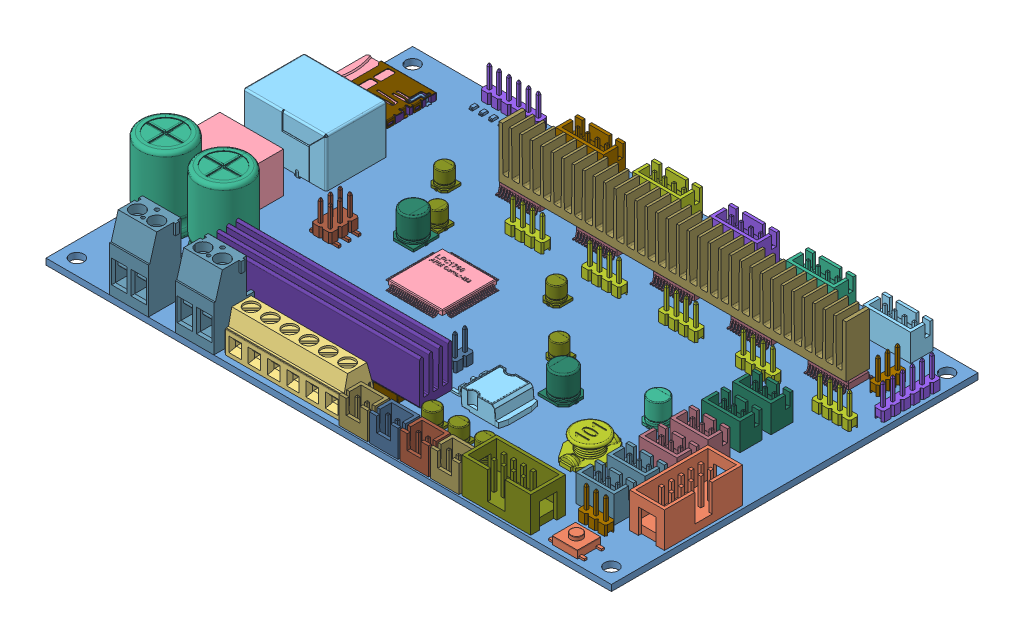
SolidWorks assembly MKS SBase V1.3, configuration Default. Lengths in mm.
Overall size (148.75 24.1 95).
84 component instances, 43 part files, 181 mates.
Components (placement in the parent):
- MKS SBase PCB-1: MKS SBase PCB [Default] at origin size (146.5 1.6 95)
- 10 pin male socket -2: 10 pin male socket  [Default] at (92.5901 0 -6.7406) x (0 0 -1) z (1 0 0) size (20.25 12.5 9) (hidden)
- 10 pin male socket -3: 10 pin male socket  [Default] at (92.5901 0 -28.4906) x (0 0 -1) z (1 0 0) size (20.25 12.5 9) (hidden)
- 6 pin terminal block-1: 6 pin terminal block [Default] at (-13.25 0 37.7021) size (30.6 13.8 8.3)
- USB socket-1: USB socket [Default] at (-15.2875 4.6912 16.0684) size (16.5 14.22 14.86)
- JST XH 4 Purple-1: JST XH 4 Purple [Default] at (56.25 0 -43.725) x (-1 0 0) z (0 0 -1) size (12.4 10.45 5.75)
- JST XH 4 Black-1: JST XH 4 Black [Default] at (36.35 0 -43.725) x (-1 0 0) z (0 0 -1) size (12.4 10.45 5.75) (hidden)
- JST XH 4 Blue-1: JST XH 4 Blue [Default] at (-3.45 0 -43.725) x (-1 0 0) z (0 0 -1) size (12.4 10.45 5.75)
- JST XH 4 Green-1: JST XH 4 Green [Default] at (16.45 0 -43.725) x (-1 0 0) z (0 0 -1) size (12.4 10.45 5.75)
- JST XH 4 Red-1: JST XH 4 Red [Default] at (-23.35 0 -43.725) x (-1 0 0) z (0 0 -1) size (12.4 10.45 5.75)
- JST XH 2 Black-1: JST XH 2 Black [Default] at (13.85 0 44.225) size (7.4 10.45 5.75)
- JST XH 2 Purple-1: JST XH 2 Purple [Default] at (21.75 0 44.225) size (7.4 10.45 5.75)
- JST XH 2 White-1: JST XH 2 White [Default] at (5.95 0 44.225) size (7.4 10.45 5.75)
- JST XH 3 Blue-1: JST XH 3 Blue [Default] at (55.4 0 14.725) x (-1 0 0) z (0 0 -1) size (9.9 10.45 5.75)
- JST XH 3 Green-1: JST XH 3 Green [Default] at (55.4 0 31.025) x (-1 0 0) z (0 0 -1) size (9.9 10.45 5.75)
- JST XH 3 Red-1: JST XH 3 Red [Default] at (55.4 0 -1.575) x (-1 0 0) z (0 0 -1) size (9.9 10.45 5.75)
- JST XH 2 White-2: JST XH 2 White [Default] at (29.65 0 44.225) size (7.4 10.45 5.75)
- 8 pin male socket -1: 8 pin male socket  [Default] at (71.2406 0 66.9901) size (17.85 12.5 9)
- JST XH 3 Blue-2: JST XH 3 Blue [Default] at (55.4 0 6.675) x (-1 0 0) z (0 0 -1) size (9.9 10.45 5.75)
- JST XH 3 Green-2: JST XH 3 Green [Default] at (55.4 0 22.975) x (-1 0 0) z (0 0 -1) size (9.9 10.45 5.75)
- JST XH 3 Red-2: JST XH 3 Red [Default] at (55.4 0 -9.625) x (-1 0 0) z (0 0 -1) size (9.9 10.45 5.75)
- microSD_Connector-1: microSD_Connector [Default] at (-65.65 0 -31.475) x (0 0 -1) z (1 0 0) size (14.1 2.14 15.45)
  - microSD_Body-1: microSD_Body [Default] at origin size (14.1 1.85 15.2)
  - microSD_Cover-1: microSD_Cover [Default] at (0 1.7 0) x (1 0 0) z (0 0 -1) size (13.95 1.9 15.2)
  - microSD_Card_Detect-1: microSD_Card_Detect [Default] at (4.99 -0.05 7.4) size (4.45 1.9 2.05)
  - microSD_Spring-2: microSD_Spring [Default] at (-3.85 1.125 6.9) x (-0.521999 -0.852946 0) z (0.852946 -0.521999 0) size (1.41 10.35 1.43)
  - microSD_Pin-1: microSD_Pin [11.15] at (5.725 -0.05 -2) x (0 0 1) z (-1 0 0) size (7.35 1.15 0.6)
  - microSD_Pin-2: microSD_Pin [11.15] at (4.625 -0.05 -2) x (0 0 1) z (-1 0 0) size (7.35 1.15 0.6)
  - microSD_Pin-3: microSD_Pin [11.35] at (3.525 -0.05 -2) x (0 0 1) z (-1 0 0) size (7.35 1.15 0.6)
  - microSD_Pin-4: microSD_Pin [11.15] at (2.425 -0.05 -2) x (0 0 1) z (-1 0 0) size (7.35 1.15 0.6)
  - microSD_Pin-5: microSD_Pin [11.35] at (1.325 -0.05 -2) x (0 0 1) z (-1 0 0) size (7.35 1.15 0.6)
  - microSD_Pin-6: microSD_Pin [11.15] at (0.225 -0.05 -2) x (0 0 1) z (-1 0 0) size (7.35 1.15 0.6)
  - microSD_Pin-7: microSD_Pin [10.75] at (-0.875 -0.05 -2) x (0 0 1) z (-1 0 0) size (7.25 1.15 0.6)
  - microSD_Pin-8: microSD_Pin [11.15] at (-1.975 -0.05 -2) x (0 0 1) z (-1 0 0) size (7.35 1.15 0.6)
- Micro SD Card-1: Micro SD Card [Default] at (-68 1.05 -33.35) x (0 0 1) z (-1 0 0) size (11 0.83 15)
- RJ45_10P_TJ3009-1: RJ45_10P_TJ3009 [Default] at (-61.925 0.35 -11.1) x (0 0 1) z (-1 0 0) size (16 15.87 21.5)
- Condensator-1: Condensator [Default] at (-65.75 0.15 24) x (-1 0 0) z (0 0 -1) size (13.15 23 13.15)
- Condensator-2: Condensator [Default] at (-50.75 0.15 24) x (-1 0 0) z (0 0 -1) size (13.15 23 13.15)
- 2.54 pins 4 x 1-1: 2.54 pins 4 x 1 [Default] at (-14.68 0 -18.75) x (1 0 0) z (0 0 -1) size (10.06 11 2.5)
- 2.54 pins 4 x 1-5: 2.54 pins 4 x 1 [Default] at (25.12 0 -18.75) x (1 0 0) z (0 0 -1) size (10.06 11 2.5)
- 2.54 pins 4 x 1-6: 2.54 pins 4 x 1 [Default] at (45.02 0 -18.75) x (1 0 0) z (0 0 -1) size (10.06 11 2.5)
- 2.54 pins 4 x 1-7: 2.54 pins 4 x 1 [Default] at (64.92 0 -18.75) x (1 0 0) z (0 0 -1) size (10.06 11 2.5)
- 2.54 pins 4 x 1-8: 2.54 pins 4 x 1 [Default] at (5.22 0 -18.75) x (1 0 0) z (0 0 -1) size (10.06 11 2.5)
- 2.54 pins 6 x 1-1: 2.54 pins 6 x 1 [Default] at (71 0 -37.8175) x (0 0 1) z (-1 0 0) size (15.09 11 2.5)
- 2.54 pins 6 x 1-3: 2.54 pins 6 x 1 [Default] at (-51.2675 0 -45.4) size (15.09 11 2.5)
- 2.54 pins 3 x 1-3: 2.54 pins 3 x 1 [Default] at (55.6125 0 36.35) size (7.47 11 2.5)
- 2.54 pins 3 x 1-4: 2.54 pins 3 x 1 [Default] at (64.6 0 -30.2125) x (0 0 -1) z (1 0 0) size (7.47 11 2.5)
- 2.54 pins 2 x 1-1: 2.54 pins 2 x 1 [Default] at (4.5 0 19.2475) x (0 0 -1) z (1 0 0) size (4.93 11 2.5)
- 2.54 pins 3 x 2-3: 2.54 pins 3 x 2 [Default] at (-42.5 0.64 7.0875) x (0 0 -1) z (1 0 0) size (7.47 8.64 7.5)
- Stepper driver heatsink-1: Stepper driver heatsink [Default] at (15.75 9.25 -28.85) x (0 0 -1) z (1 0 0) size (6 13.5 90)
- Stepper driver-1: Stepper driver [Default] at (55.75 1.35 -28.85) x (0 0 -1) z (1 0 0) size (8 2.5 10.5)
- Stepper driver-2: Stepper driver [Default] at (35.75 1.35 -28.85) x (0 0 -1) z (1 0 0) size (8 2.5 10.5)
- Stepper driver-3: Stepper driver [Default] at (15.75 1.35 -28.85) x (0 0 -1) z (1 0 0) size (8 2.5 10.5)
- Stepper driver-4: Stepper driver [Default] at (-4.25 1.35 -28.85) x (0 0 -1) z (1 0 0) size (8 2.5 10.5)
- Stepper driver-5: Stepper driver [Default] at (-24.25 1.35 -28.85) x (0 0 -1) z (1 0 0) size (8 2.5 10.5)
- Power terminal block-1: Power terminal block [Default] at (-51.75 0 42.25) x (-1 0 0) z (0 0 -1) size (10.55 20.8 10.5)
- Power terminal block-2: Power terminal block [Default] at (-34.75 0 42.25) x (-1 0 0) z (0 0 -1) size (10.55 20.8 10.5)
- Elco100_35-5: Elco100_35 [Default] at (-30.25 0.64 -4.7) x (0 0 1) z (-1 0 0) size (6.6 6.95 7)
- Elco100_35-6: Elco100_35 [Default] at (24.65 0.64 11.3) x (0 0 -1) z (1 0 0) size (6.6 6.95 7)
- Elco100_35-7: Elco100_35 [Default] at (-32.05 0.64 -36) x (0 0 -1) z (1 0 0) size (6.6 6.95 7)
- Elco100_35-8: Elco100_35 [Default] at (-12.05 0.64 -36) x (0 0 -1) z (1 0 0) size (6.6 6.95 7)
- Elco100_35-9: Elco100_35 [Default] at (7.95 0.64 -36) x (0 0 -1) z (1 0 0) size (6.6 6.95 7)
- Elco100_35-10: Elco100_35 [Default] at (27.95 0.64 -36) x (0 0 -1) z (1 0 0) size (6.6 6.95 7)
- Elco100_35-11: Elco100_35 [Default] at (47.95 0.64 -36) x (0 0 -1) z (1 0 0) size (6.6 6.95 7)
- Elco10_35-1: Elco10_35 [Default] at (35.2 0.64 35.25) size (4.3 4.65 4.6)
- Elco10_35-2: Elco10_35 [Default] at (28.35 0.64 35.25) size (4.3 4.65 4.6)
- Elco10_35-3: Elco10_35 [Default] at (21.5 0.64 35.25) size (4.3 4.65 4.6)
- Elco10_35-4: Elco10_35 [Default] at (14.65 0.64 35.25) size (4.3 4.65 4.6)
- Power FAT heatsink-1: Power FAT heatsink [Default] at (-16.55 2 30.7) size (55 11.25 8.49)
- Power FAT-1: Power FAT [Default] at (-34.925 0 30.7) x (-1 0 0) z (0 0 -1) size (6.35 2 11)
- Power FAT-2: Power FAT [Default] at (-22.675 0 30.7) x (-1 0 0) z (0 0 -1) size (6.35 2 11)
- Power FAT-3: Power FAT [Default] at (-10.425 0 30.7) x (-1 0 0) z (0 0 -1) size (6.35 2 11)
- Power FAT-4: Power FAT [Default] at (1.825 0 30.7) x (-1 0 0) z (0 0 -1) size (6.35 2 11)
- Series of LEDs-1: Series of LEDs [Default] at (-46.425 0 -41.575) size (10.85 0.6 1.75)
- Reset button-1: Reset button [Default] at (59.9 0 43.2) size (9.25 2.95 6.02)
- 4 LEDs power outputs-1: 4 LEDs power outputs [Default] at (-12.2 0 25.075) size (37.6 0.6 1.75)
- LPC1768 ARM Cortex M3-1: LPC1768 ARM Cortex M3 [Default] at (-15.75 0 2.3) size (17 1.4 17)
- Elco10_35-6: Elco10_35 [Default] at (-29.9 0.64 -10.6) x (0 0 1) z (-1 0 0) size (4.3 4.65 4.6)
- Elco10_35-7: Elco10_35 [Default] at (2.4 0.64 -9.1) size (4.3 4.65 4.6)
- Elco10_35-8: Elco10_35 [Default] at (15.6 0.64 3.35) size (4.3 4.65 4.6)
- Elco10_35-9: Elco10_35 [Default] at (-37.9 0.64 -20.4) size (4.3 4.65 4.6)
- L7812C2T Power regulator-1: L7812C2T Power regulator [Default] at (19 0 22.1) x (0 0 1) z (-1 0 0) size (10 4.5 15)
- Elco22_35-1: Elco22_35 [Default] at (42.9 0.64 5) size (5.3 6.15 5.5)
- Inductance 101-1: Inductance 101 [Default] at (41.25 0 21) size (10 5 13)
Mates (geometry in assembly coordinates):
- Coincident3: coincident aligned: plane of MKS SBase PCB-1 through (0 0 0) normal (1 0 0)
- Coincident8: coincident aligned: plane of 10 pin male socket -2 through (72.5 9.1 33) normal (1 0 0); plane of 10 pin male socket -3 through (72.5 9.1 11.25) normal (1 0 0)
- Distance3: distance = 14.5 mm aligned: plane of 10 pin male socket -2 through (63.5 9.1 33) normal (0 0 1); plane of MKS SBase PCB-1 through (-73.25 -1.6 47.5) normal (0 0 1)
- Distance4: distance = 42 mm anti-aligned: plane of 10 pin male socket -2 through (63.5 9.1 33) normal (0 0 1); plane of 10 pin male socket -3 through (63.5 9.1 -9) normal (0 0 -1)
- Distance5: distance = 0.75 mm aligned: plane of 10 pin male socket -2 through (72.5 9.1 33) normal (1 0 0); plane of MKS SBase PCB-1 through (73.25 -1.6 -47.5) normal (1 0 0)
- Coincident15: coincident anti-aligned: plane of MKS SBase PCB-1 through (0 0 0) normal (0 1 0); plane of 6 pin terminal block-1 through (1.75 0 46) normal (0 -1 0)
- Distance6: distance = 71.5 mm aligned: plane of 6 pin terminal block-1 through (1.75 7.1842 38.5787) normal (1 0 0); plane of MKS SBase PCB-1 through (73.25 -1.6 -47.5) normal (1 0 0)
- Distance7: distance = 1.5 mm aligned: plane of 6 pin terminal block-1 through (1.75 5.6981 46) normal (0 0 1); plane of MKS SBase PCB-1 through (-73.25 -1.6 47.5) normal (0 0 1)
- Coincident18: coincident anti-aligned: plane of MKS SBase PCB-1 through (0 0 0) normal (0 1 0); plane of USB socket-1 through (-72.95 0 2.75) normal (0 -1 0)
- Distance8: distance = 44.75 mm anti-aligned: plane of USB socket-1 through (-72.95 10.5 2.75) normal (0 0 -1); plane of MKS SBase PCB-1 through (-73.25 -1.6 47.5) normal (0 0 1)
- Distance9: distance = 0.3 mm aligned: plane of USB socket-1 through (-72.95 0 2.75) normal (-1 0 0); plane of MKS SBase PCB-1 through (-73.25 -1.6 -47.5) normal (-1 0 0)
- Coincident21: coincident aligned: plane of JST XH 4 Black-1 through (36.35 0 -43.725) normal (0 -1 0); plane of JST XH 4 Blue-1 through (-3.45 0 -43.725) normal (0 -1 0)
- Coincident22: coincident aligned: plane of JST XH 4 Purple-1 through (56.25 0 -43.725) normal (0 -1 0); plane of JST XH 4 Blue-1 through (-3.45 0 -43.725) normal (0 -1 0)
- Coincident26: coincident aligned: plane of JST XH 4 Black-1 through (42.55 7 -40.85) normal (0 0 1); plane of JST XH 4 Blue-1 through (2.75 7 -40.85) normal (0 0 1)
- Coincident27: coincident aligned: plane of JST XH 4 Blue-1 through (2.75 7 -40.85) normal (0 0 1); plane of JST XH 4 Green-1 through (22.65 7 -40.85) normal (0 0 1)
- Distance15: distance = 0.9 mm aligned: plane of MKS SBase PCB-1 through (-73.25 -1.6 -47.5) normal (0 0 -1); plane of JST XH 4 Red-1 through (-17.15 7 -46.6) normal (0 0 -1)
- Coincident37: coincident anti-aligned: plane of MKS SBase PCB-1 through (0 0 0) normal (0 1 0); plane of JST XH 4 Red-1 through (-23.35 0 -43.725) normal (0 -1 0)
- Distance16: distance = 43.7 mm aligned: plane of MKS SBase PCB-1 through (-73.25 -1.6 -47.5) normal (-1 0 0); plane of JST XH 4 Red-1 through (-29.55 7 -40.85) normal (-1 0 0)
- Coincident39: coincident aligned: plane of JST XH 4 Blue-1 through (2.75 7 -40.85) normal (0 0 1); plane of JST XH 4 Red-1 through (-17.15 7 -40.85) normal (0 0 1)
- Coincident40: coincident anti-aligned: plane of MKS SBase PCB-1 through (0 0 0) normal (0 1 0); plane of JST XH 4 Blue-1 through (-3.45 0 -43.725) normal (0 -1 0)
- Distance17: distance = 7.5 mm anti-aligned: plane of JST XH 4 Blue-1 through (-9.65 7 -40.85) normal (-1 0 0); plane of JST XH 4 Red-1 through (-17.15 7 -40.85) normal (1 0 0)
- Distance18: distance = 7.5 mm anti-aligned: plane of JST XH 4 Green-1 through (10.25 7 -40.85) normal (-1 0 0); plane of JST XH 4 Blue-1 through (2.75 7 -40.85) normal (1 0 0)
- Distance19: distance = 7.5 mm anti-aligned: plane of JST XH 4 Black-1 through (30.15 7 -40.85) normal (-1 0 0); plane of JST XH 4 Green-1 through (22.65 7 -40.85) normal (1 0 0)
- Coincident44: coincident aligned: plane of JST XH 4 Purple-1 through (62.45 7 -46.6) normal (0 0 -1); plane of JST XH 4 Black-1 through (42.55 7 -46.6) normal (0 0 -1)
- Distance20: distance = 7.5 mm anti-aligned: plane of JST XH 4 Purple-1 through (50.05 7 -40.85) normal (-1 0 0); plane of JST XH 4 Black-1 through (42.55 7 -40.85) normal (1 0 0)
- Coincident47: coincident aligned: plane of JST XH 2 Purple-1 through (18.05 7 47.1) normal (0 0 1); plane of JST XH 2 White-2 through (25.95 7 47.1) normal (0 0 1)
- Coincident48: coincident aligned: plane of JST XH 2 Black-1 through (10.15 7 47.1) normal (0 0 1); plane of JST XH 2 Purple-1 through (18.05 7 47.1) normal (0 0 1)
- Coincident49: coincident aligned: plane of JST XH 2 Black-1 through (10.15 7 47.1) normal (0 0 1); plane of JST XH 2 White-1 through (2.25 7 47.1) normal (0 0 1)
- Coincident50: coincident aligned: plane of JST XH 2 Black-1 through (13.85 0 44.225) normal (0 -1 0); plane of JST XH 2 White-2 through (29.65 0 44.225) normal (0 -1 0)
- Coincident51: coincident aligned: plane of JST XH 2 Purple-1 through (21.75 0 44.225) normal (0 -1 0); plane of JST XH 2 White-2 through (29.65 0 44.225) normal (0 -1 0)
- Coincident52: coincident aligned: plane of JST XH 2 Purple-1 through (21.75 0 44.225) normal (0 -1 0); plane of JST XH 2 White-1 through (5.95 0 44.225) normal (0 -1 0)
- Coincident53: coincident anti-aligned: plane of MKS SBase PCB-1 through (0 0 0) normal (0 1 0); plane of JST XH 2 Black-1 through (13.85 0 44.225) normal (0 -1 0)
- Coincident54: coincident anti-aligned: plane of MKS SBase PCB-1 through (0 0 0) normal (0 1 0); plane of 8 pin male socket -1 through (71.2406 0 66.9901) normal (0 -1 0)
- Distance21: distance = 21.5 mm aligned: plane of 8 pin male socket -1 through (51.75 9.1 37.9) normal (1 0 0); plane of MKS SBase PCB-1 through (73.25 -1.6 -47.5) normal (1 0 0)
- Distance22: distance = 0.6 mm aligned: plane of 8 pin male socket -1 through (33.9 9.1 46.9) normal (0 0 1); plane of MKS SBase PCB-1 through (-73.25 -1.6 47.5) normal (0 0 1)
- Distance23: distance = 0.4 mm aligned: plane of JST XH 2 White-1 through (2.25 7 47.1) normal (0 0 1); plane of MKS SBase PCB-1 through (-73.25 -1.6 47.5) normal (0 0 1)
- Distance24: distance = 0.5 mm anti-aligned: plane of 6 pin terminal block-1 through (1.75 7.1842 38.5787) normal (1 0 0); plane of JST XH 2 White-1 through (2.25 7 41.35) normal (-1 0 0)
- Distance25: distance = 0.5 mm anti-aligned: plane of JST XH 2 White-1 through (9.65 7 41.35) normal (1 0 0); plane of JST XH 2 Black-1 through (10.15 7 41.35) normal (-1 0 0)
- Distance26: distance = 0.5 mm anti-aligned: plane of JST XH 2 Black-1 through (17.55 7 41.35) normal (1 0 0); plane of JST XH 2 Purple-1 through (18.05 7 41.35) normal (-1 0 0)
- Distance27: distance = 0.5 mm anti-aligned: plane of JST XH 2 White-2 through (25.95 7 41.35) normal (-1 0 0); plane of JST XH 2 Purple-1 through (25.45 7 41.35) normal (1 0 0)
- Distance28: distance = 12.9 mm aligned: plane of JST XH 3 Red-2 through (60.35 7 -6.75) normal (1 0 0); plane of MKS SBase PCB-1 through (73.25 -1.6 -47.5) normal (1 0 0)
- Coincident64: coincident anti-aligned: plane of MKS SBase PCB-1 through (0 0 0) normal (0 1 0); plane of JST XH 3 Red-2 through (55.4 0 -9.625) normal (0 -1 0)
- Coincident65: coincident aligned: plane of JST XH 3 Red-1 through (50.45 7 1.3) normal (-1 0 0); plane of JST XH 3 Red-2 through (50.45 7 -6.75) normal (-1 0 0)
- Coincident66: coincident aligned: plane of JST XH 3 Red-1 through (55.4 0 -1.575) normal (0 -1 0); plane of JST XH 3 Red-2 through (55.4 0 -9.625) normal (0 -1 0)
- Coincident67: coincident aligned: plane of JST XH 3 Red-1 through (50.45 7 1.3) normal (-1 0 0); plane of JST XH 3 Blue-2 through (50.45 7 9.55) normal (-1 0 0)
- Coincident68: coincident aligned: plane of JST XH 3 Blue-2 through (55.4 0 6.675) normal (0 -1 0); plane of JST XH 3 Red-2 through (55.4 0 -9.625) normal (0 -1 0)
- Coincident69: coincident aligned: plane of JST XH 3 Blue-1 through (50.45 7 17.6) normal (-1 0 0); plane of JST XH 3 Blue-2 through (50.45 7 9.55) normal (-1 0 0)
- Coincident70: coincident aligned: plane of JST XH 3 Blue-1 through (55.4 0 14.725) normal (0 -1 0); plane of JST XH 3 Red-2 through (55.4 0 -9.625) normal (0 -1 0)
- Coincident71: coincident aligned: plane of JST XH 3 Blue-1 through (50.45 7 17.6) normal (-1 0 0); plane of JST XH 3 Green-2 through (50.45 7 25.85) normal (-1 0 0)
- Coincident72: coincident aligned: plane of JST XH 3 Green-2 through (55.4 0 22.975) normal (0 -1 0); plane of JST XH 3 Red-2 through (55.4 0 -9.625) normal (0 -1 0)
- Coincident73: coincident aligned: plane of JST XH 3 Green-1 through (50.45 7 33.9) normal (-1 0 0); plane of JST XH 3 Green-2 through (50.45 7 25.85) normal (-1 0 0)
- Coincident74: coincident aligned: plane of JST XH 3 Green-1 through (55.4 0 31.025) normal (0 -1 0); plane of JST XH 3 Red-2 through (55.4 0 -9.625) normal (0 -1 0)
- Distance29: distance = 60 mm anti-aligned: plane of JST XH 3 Red-2 through (60.35 7 -12.5) normal (0 0 -1); plane of MKS SBase PCB-1 through (-73.25 -1.6 47.5) normal (0 0 1)
- Distance31: distance = 2.3 mm anti-aligned: plane of JST XH 3 Green-1 through (60.35 7 28.15) normal (0 0 -1); plane of JST XH 3 Green-2 through (60.35 7 25.85) normal (0 0 1)
- Distance32: distance = 2.5 mm anti-aligned: plane of JST XH 3 Blue-1 through (60.35 7 17.6) normal (0 0 1); plane of JST XH 3 Green-2 through (60.35 7 20.1) normal (0 0 -1)
- Distance33: distance = 2.3 mm anti-aligned: plane of JST XH 3 Blue-2 through (60.35 7 9.55) normal (0 0 1); plane of JST XH 3 Blue-1 through (60.35 7 11.85) normal (0 0 -1)
- Distance34: distance = 2.5 mm anti-aligned: plane of JST XH 3 Blue-2 through (60.35 7 3.8) normal (0 0 -1); plane of JST XH 3 Red-1 through (60.35 7 1.3) normal (0 0 1)
- Distance35: distance = 2.3 mm anti-aligned: plane of JST XH 3 Red-2 through (60.35 7 -6.75) normal (0 0 1); plane of JST XH 3 Red-1 through (60.35 7 -4.45) normal (0 0 -1)
- Coincident85: coincident aligned: plane of MKS SBase PCB-1 through (-73.25 -1.6 -47.5) normal (-1 0 0); plane of microSD_Connector-1/microSD_Body-1 through (-73.25 1.7 -24.65) normal (-1 0 0)
- Coincident86: coincident anti-aligned: plane of MKS SBase PCB-1 through (0 0 0) normal (0 1 0); plane of microSD_Connector-1/microSD_Body-1 through (-65.65 0 -31.475) normal (0 -1 0)
- Distance37: distance = 9.05 mm aligned: plane of microSD_Connector-1/microSD_Cover-1 through (-65.65 1.7 -38.45) normal (0 0 -1); plane of MKS SBase PCB-1 through (-73.25 -1.6 -47.5) normal (0 0 -1)
- Coincident92: coincident aligned: plane of microSD_Connector-1/microSD_Cover-1 through (-65.65 1.85 -31.475) normal (0 1 0); plane of Micro SD Card-1 through (-74.9 1.85 -37.5) normal (0 1 0)
- Parallel2: parallel anti-aligned: plane of microSD_Connector-1/microSD_Cover-1 through (-65.65 1.7 -38.3) normal (0 0 1); plane of Micro SD Card-1 through (-74.9 1.55 -38.1) normal (0 0 -1)
- Distance39: distance = 0.3 mm aligned: plane of Micro SD Card-1 through (-64.3 1.025 -37.65) normal (0 0 -1); plane of microSD_Connector-1/microSD_Pin-1 through (-68.4517 0.1 -37.35) normal (0 0 -1)
- Distance41: distance = 2.25 mm aligned: plane of microSD_Connector-1/microSD_Body-1 through (-73.25 1.7 -24.65) normal (-1 0 0); plane of Micro SD Card-1 through (-75.5 1.55 -27.7) normal (-1 0 0)
- Coincident94: coincident anti-aligned: plane of MKS SBase PCB-1 through (0 0 0) normal (0 1 0); plane of RJ45_10P_TJ3009-1 through (-61.925 0 -11.1) normal (0 -1 0)
- Distance43: distance = 0.4 mm aligned: plane of RJ45_10P_TJ3009-1 through (-72.85 13.02 -11.1) normal (-1 0 0); plane of MKS SBase PCB-1 through (-73.25 -1.6 -47.5) normal (-1 0 0)
- Distance44: distance = 28.5 mm aligned: plane of RJ45_10P_TJ3009-1 through (-61.925 13.02 -19) normal (0 0 -1); plane of MKS SBase PCB-1 through (-73.25 -1.6 -47.5) normal (0 0 -1)
- Coincident95: coincident aligned: plane of Condensator-1 through (-65.75 0.15 24) normal (0 0 -1); plane of Condensator-2 through (-50.75 0.15 24) normal (0 0 -1)
- Distance45: distance = 7.5 mm aligned: plane of Condensator-1 through (-65.75 0.15 24) normal (-1 0 0); plane of MKS SBase PCB-1 through (-73.25 -1.6 -47.5) normal (-1 0 0)
- Coincident97: coincident aligned: plane of Condensator-1 through (-65.75 0.15 24) normal (0 -1 0); plane of Condensator-2 through (-50.75 0.15 24) normal (0 -1 0)
- Coincident98: coincident anti-aligned: plane of MKS SBase PCB-1 through (0 0 0) normal (0 1 0); plane of Condensator-1 through (-65.75 0 24) normal (0 -1 0)
- Distance46: distance = 15 mm aligned: plane of Condensator-1 through (-65.75 0.15 24) normal (-1 0 0); plane of Condensator-2 through (-50.75 0.15 24) normal (-1 0 0)
- Distance47: distance = 23.5 mm anti-aligned: plane of Condensator-2 through (-50.75 0.15 24) normal (0 0 -1); plane of MKS SBase PCB-1 through (-73.25 -1.6 47.5) normal (0 0 1)
- Coincident101: coincident anti-aligned: plane of MKS SBase PCB-1 through (0 0 0) normal (0 1 0); plane of 2.54 pins 4 x 1-1 through (-14.68 0 -18.75) normal (0 -1 0)
- Distance48: distance = 30 mm anti-aligned: plane of 2.54 pins 4 x 1-1 through (-17.715 2.54 -17.5) normal (0 0 1); plane of MKS SBase PCB-1 through (-73.25 -1.6 -47.5) normal (0 0 -1)
- Coincident104: coincident anti-aligned: plane of JST XH 4 Blue-1 through (-9.65 7 -40.85) normal (-1 0 0); plane of 2.54 pins 4 x 1-1 through (-9.65 2.54 -19.5) normal (1 0 0)
- Coincident108: coincident aligned: plane of 2.54 pins 4 x 1-5 through (25.12 0 -18.75) normal (0 -1 0); plane of 2.54 pins 4 x 1-8 through (5.22 0 -18.75) normal (0 -1 0)
- Coincident109: coincident aligned: plane of 2.54 pins 4 x 1-5 through (25.12 0 -18.75) normal (0 -1 0); plane of 2.54 pins 4 x 1-6 through (45.02 0 -18.75) normal (0 -1 0)
- Coincident110: coincident aligned: plane of 2.54 pins 4 x 1-6 through (45.02 0 -18.75) normal (0 -1 0); plane of 2.54 pins 4 x 1-7 through (64.92 0 -18.75) normal (0 -1 0)
- Coincident111: coincident anti-aligned: plane of MKS SBase PCB-1 through (0 0 0) normal (0 1 0); plane of 2.54 pins 4 x 1-8 through (5.22 0 -18.75) normal (0 -1 0)
- Coincident112: coincident aligned: plane of 2.54 pins 4 x 1-1 through (-16.775 2.54 -20) normal (0 0 -1); plane of 2.54 pins 4 x 1-8 through (0.56 2.54 -20) normal (0 0 -1)
- Coincident113: coincident aligned: plane of 2.54 pins 4 x 1-5 through (20.46 2.54 -20) normal (0 0 -1); plane of 2.54 pins 4 x 1-8 through (0.56 2.54 -20) normal (0 0 -1)
- Coincident114: coincident aligned: plane of 2.54 pins 4 x 1-5 through (20.46 2.54 -20) normal (0 0 -1); plane of 2.54 pins 4 x 1-6 through (40.36 2.54 -20) normal (0 0 -1)
- Coincident115: coincident aligned: plane of 2.54 pins 4 x 1-6 through (40.36 2.54 -20) normal (0 0 -1); plane of 2.54 pins 4 x 1-7 through (62.825 2.54 -20) normal (0 0 -1)
- Coincident116: coincident anti-aligned: plane of JST XH 4 Green-1 through (10.25 7 -40.85) normal (-1 0 0); plane of 2.54 pins 4 x 1-8 through (10.25 2.54 -19.5) normal (1 0 0)
- Coincident117: coincident anti-aligned: plane of JST XH 4 Black-1 through (30.15 7 -40.85) normal (-1 0 0); plane of 2.54 pins 4 x 1-5 through (30.15 2.54 -19.5) normal (1 0 0)
- Coincident118: coincident anti-aligned: plane of JST XH 4 Purple-1 through (50.05 7 -40.85) normal (-1 0 0); plane of 2.54 pins 4 x 1-6 through (50.05 2.54 -19.5) normal (1 0 0)
- Distance49: distance = 9.84 mm anti-aligned: plane of 2.54 pins 4 x 1-6 through (50.05 2.54 -19.5) normal (1 0 0); plane of 2.54 pins 4 x 1-7 through (59.89 2.54 -18) normal (-1 0 0)
- Coincident121: coincident aligned: plane of 2.54 pins 6 x 1-1 through (71 0 -37.8175) normal (0 -1 0); plane of 2.54 pins 6 x 1-3 through (-51.2675 0 -45.4) normal (0 -1 0)
- Coincident122: coincident anti-aligned: plane of MKS SBase PCB-1 through (0 0 0) normal (0 1 0); plane of 2.54 pins 6 x 1-3 through (-51.2675 0 -45.4) normal (0 -1 0)
- Distance50: distance = 0.85 mm aligned: plane of 2.54 pins 6 x 1-3 through (-46.975 2.54 -46.65) normal (0 0 -1); plane of MKS SBase PCB-1 through (-73.25 -1.6 -47.5) normal (0 0 -1)
- Distance51: distance = 20.8 mm aligned: plane of MKS SBase PCB-1 through (-73.25 -1.6 -47.5) normal (-1 0 0); plane of 2.54 pins 6 x 1-3 through (-52.45 2.54 -46.15) normal (-1 0 0)
- Distance52: distance = 1 mm aligned: plane of 2.54 pins 6 x 1-1 through (72.25 2.54 -33.525) normal (1 0 0); plane of MKS SBase PCB-1 through (73.25 -1.6 -47.5) normal (1 0 0)
- Distance53: distance = 8.5 mm aligned: plane of 2.54 pins 6 x 1-1 through (71.75 2.54 -39) normal (0 0 -1); plane of MKS SBase PCB-1 through (-73.25 -1.6 -47.5) normal (0 0 -1)
- Coincident127: coincident aligned: plane of 2.54 pins 3 x 1-3 through (55.6125 0 36.35) normal (0 -1 0); plane of 2.54 pins 3 x 1-4 through (64.6 0 -30.2125) normal (0 -1 0)
- Coincident128: coincident anti-aligned: plane of MKS SBase PCB-1 through (0 0 0) normal (0 1 0); plane of 2.54 pins 3 x 1-3 through (55.6125 0 36.35) normal (0 -1 0)
- Distance54: distance = 11 mm aligned: plane of 2.54 pins 3 x 1-4 through (63.85 2.54 -36.5) normal (0 0 -1); plane of MKS SBase PCB-1 through (-73.25 -1.6 -47.5) normal (0 0 -1)
- Distance55: distance = 9.9 mm anti-aligned: plane of 2.54 pins 3 x 1-4 through (63.35 2.54 -31.965) normal (-1 0 0); plane of MKS SBase PCB-1 through (73.25 -1.6 -47.5) normal (1 0 0)
- Distance56: distance = 11.35 mm aligned: plane of 2.54 pins 3 x 1-3 through (61.9 2.54 35.6) normal (1 0 0); plane of MKS SBase PCB-1 through (73.25 -1.6 -47.5) normal (1 0 0)
- Distance57: distance = 9.9 mm aligned: plane of 2.54 pins 3 x 1-3 through (61.53 2.54 37.6) normal (0 0 1); plane of MKS SBase PCB-1 through (-73.25 -1.6 47.5) normal (0 0 1)
- Coincident133: coincident anti-aligned: plane of MKS SBase PCB-1 through (0 0 0) normal (0 1 0); plane of 2.54 pins 2 x 1-1 through (4.5 0 19.2475) normal (0 -1 0)
- Distance58: distance = 32 mm anti-aligned: plane of 2.54 pins 2 x 1-1 through (3.75 2.54 15.5) normal (0 0 -1); plane of MKS SBase PCB-1 through (-73.25 -1.6 47.5) normal (0 0 1)
- Distance59: distance = 1 mm aligned: plane of 2.54 pins 2 x 1-1 through (3.25 2.54 18.435) normal (-1 0 0); plane of JST XH 2 White-1 through (2.25 7 41.35) normal (-1 0 0)
- Coincident136: coincident anti-aligned: plane of MKS SBase PCB-1 through (0 0 0) normal (0 1 0); plane of 2.54 pins 3 x 2-3 through (-39.68 0 6.7675) normal (0 -1 0)
- Distance60: distance = 34.5 mm anti-aligned: plane of 2.54 pins 3 x 2-3 through (-38.75 3.18 5.335) normal (1 0 0); plane of MKS SBase PCB-1 through (-73.25 -1.6 -47.5) normal (-1 0 0)
- Distance61: distance = 46.7 mm anti-aligned: plane of 2.54 pins 3 x 2-3 through (-39.25 3.18 0.8) normal (0 0 -1); plane of MKS SBase PCB-1 through (-73.25 -1.6 47.5) normal (0 0 1)
- Distance62: distance = 15.65 mm aligned: plane of Stepper driver heatsink-1 through (15.75 9.25 -31.85) normal (0 0 -1); plane of MKS SBase PCB-1 through (-73.25 -1.6 -47.5) normal (0 0 -1)
- Distance63: distance = 12.5 mm aligned: plane of Stepper driver heatsink-1 through (60.75 16 -31.85) normal (1 0 0); plane of MKS SBase PCB-1 through (73.25 -1.6 -47.5) normal (1 0 0)
- Symmetric1: symmetric aligned: plane of Stepper driver heatsink-1 through (15.75 9.25 -28.85) normal (0 0 -1); plane of Stepper driver-1 through (61 0.2 -31.475) normal (0 0 -1); plane of Stepper driver-1 through (61 2.5 -26.225) normal (0 0 1)
- Coincident141: coincident anti-aligned: plane of Stepper driver heatsink-1 through (60.75 2.5 -31.85) normal (0 -1 0); plane of Stepper driver-1 through (61 2.5 -31.475) normal (0 1 0)
- Coincident142: coincident anti-aligned: plane of MKS SBase PCB-1 through (0 0 0) normal (0 1 0); plane of Stepper driver-1 through (60.3214 0 -24.85) normal (0 -1 0)
- Symmetric2: symmetric aligned: plane of Stepper driver heatsink-1 through (15.75 9.25 -28.85) normal (1 0 0); plane of Stepper driver-3 through (10.5 1.35 -28.85) normal (-1 0 0); plane of Stepper driver-3 through (21 1.35 -28.85) normal (1 0 0)
- Coincident143: coincident aligned: plane of Power terminal block-1 through (-56.75 0 47.5) normal (0 -1 0); plane of Power terminal block-2 through (-39.75 0 47.5) normal (0 -1 0)
- Coincident145: coincident aligned: plane of Power terminal block-1 through (-56.75 0 37) normal (0 0 -1); plane of Power terminal block-2 through (-39.75 0 37) normal (0 0 -1)
- Coincident146: coincident anti-aligned: plane of MKS SBase PCB-1 through (0 0 0) normal (0 1 0); plane of Power terminal block-1 through (-56.75 0 47.5) normal (0 -1 0)
- Coincident148: coincident aligned: plane of MKS SBase PCB-1 through (-73.25 -1.6 47.5) normal (0 0 1); plane of Power terminal block-1 through (-56.75 11.7 47.5) normal (0 0 1)
- Distance64: distance = 16.5 mm aligned: plane of Power terminal block-1 through (-56.75 0 42.25) normal (-1 0 0); plane of MKS SBase PCB-1 through (-73.25 -1.6 -47.5) normal (-1 0 0)
- Distance65: distance = 7 mm anti-aligned: plane of Power terminal block-2 through (-39.75 0 42.25) normal (-1 0 0); plane of Power terminal block-1 through (-46.75 0 42.25) normal (1 0 0)
- Coincident162: coincident aligned: plane of Elco100_35-5 through (-30.25 0 -4.7) normal (0 -1 0); plane of Elco100_35-6 through (24.65 0 11.3) normal (0 -1 0)
- Coincident163: coincident aligned: plane of Elco100_35-6 through (24.65 0 11.3) normal (0 -1 0); plane of Elco100_35-7 through (-32.05 0 -36) normal (0 -1 0)
- Coincident164: coincident anti-aligned: plane of MKS SBase PCB-1 through (0 0 0) normal (0 1 0); plane of Elco100_35-5 through (-30.25 0 -4.7) normal (0 -1 0)
- Distance69: distance = 14.8 mm anti-aligned: plane of Elco100_35-7 through (-30.1642 0 -32.7) normal (0 0 1); plane of MKS SBase PCB-1 through (-73.25 -1.6 -47.5) normal (0 0 -1)
- Distance70: distance = 18.2 mm anti-aligned: plane of Elco100_35-7 through (-35.35 0 -32.7) normal (-1 0 0); plane of JST XH 4 Red-1 through (-17.15 7 -40.85) normal (1 0 0)
- Distance71: distance = 46.3 mm anti-aligned: plane of Elco100_35-5 through (-26.95 0 -8) normal (1 0 0); plane of MKS SBase PCB-1 through (-73.25 -1.6 -47.5) normal (-1 0 0)
- Distance73: distance = 51.9 mm anti-aligned: plane of Elco100_35-6 through (21.35 0 14.6) normal (-1 0 0); plane of MKS SBase PCB-1 through (73.25 -1.6 -47.5) normal (1 0 0)
- Distance74: distance = 39.5 mm anti-aligned: plane of MKS SBase PCB-1 through (-73.25 -1.6 47.5) normal (0 0 1); plane of Elco100_35-6 through (21.35 0 8) normal (0 0 -1)
- Coincident173: coincident anti-aligned: plane of MKS SBase PCB-1 through (0 0 0) normal (0 1 0); plane of Elco10_35-1 through (35.2 0 35.25) normal (0 -1 0)
- Distance75: distance = 14.4 mm anti-aligned: plane of Elco10_35-1 through (33.05 0 33.1) normal (0 0 -1); plane of MKS SBase PCB-1 through (-73.25 -1.6 47.5) normal (0 0 1)
- Distance76: distance = 40.2 mm anti-aligned: plane of Elco10_35-1 through (33.05 0 36.5515) normal (-1 0 0); plane of MKS SBase PCB-1 through (73.25 -1.6 -47.5) normal (1 0 0)
- Coincident176: coincident anti-aligned: plane of MKS SBase PCB-1 through (0 0 0) normal (0 1 0); plane of Power FAT-1 through (-34.925 0 30.7) normal (0 -1 0)
- Distance77: distance = 20.8 mm anti-aligned: plane of Power FAT-1 through (-31.75 2 26.7) normal (0 0 -1); plane of MKS SBase PCB-1 through (-73.25 -1.6 47.5) normal (0 0 1)
- Distance78: distance = 41.5 mm anti-aligned: plane of Power FAT-1 through (-31.75 2 34.7) normal (1 0 0); plane of MKS SBase PCB-1 through (-73.25 -1.6 -47.5) normal (-1 0 0)
- Symmetric4: symmetric aligned: plane of Power FAT heatsink-1 through (-16.55 2 30.7) normal (1 0 0); plane of Power FAT-1 through (-38.1 2 34.7) normal (-1 0 0); plane of Power FAT-4 through (5 2 34.7) normal (1 0 0)
- Coincident179: coincident anti-aligned: plane of Power FAT heatsink-1 through (10.95 2 34.95) normal (0 -1 0); plane of Power FAT-3 through (-10.425 2 30.7) normal (0 1 0)
- Coincident180: coincident anti-aligned: plane of Power FAT heatsink-1 through (-16.55 2 30.7) normal (0 0 1); plane of Power FAT-1 through (-34.925 0 30.7) normal (0 0 -1)
- Coincident181: coincident anti-aligned: plane of MKS SBase PCB-1 through (0 0 0) normal (0 1 0); plane of Series of LEDs-1 through (-46.425 0 -41.575) normal (0 -1 0)
- Distance79: distance = 32.25 mm anti-aligned: plane of Series of LEDs-1 through (-41 0.6 -42.2) normal (1 0 0); plane of MKS SBase PCB-1 through (-73.25 -1.6 -47.5) normal (-1 0 0)
- Distance80: distance = 6.8 mm anti-aligned: plane of Series of LEDs-1 through (-51.85 0.25 -40.7) normal (0 0 1); plane of MKS SBase PCB-1 through (-73.25 -1.6 -47.5) normal (0 0 -1)
- Coincident184: coincident anti-aligned: plane of MKS SBase PCB-1 through (0 0 0) normal (0 1 0); plane of Reset button-1 through (59.9 0 43.2) normal (0 -1 0)
- Distance81: distance = 7.3 mm anti-aligned: plane of Reset button-1 through (56.65 1.75 40.2) normal (0 0 -1); plane of MKS SBase PCB-1 through (-73.25 -1.6 47.5) normal (0 0 1)
- Distance82: distance = 16.6 mm anti-aligned: plane of Reset button-1 through (56.65 1.75 40.2) normal (-1 0 0); plane of MKS SBase PCB-1 through (73.25 -1.6 -47.5) normal (1 0 0)
- Coincident187: coincident anti-aligned: plane of MKS SBase PCB-1 through (0 0 0) normal (0 1 0); plane of 10 pin male socket -2 through (92.5901 0 -6.7406) normal (0 -1 0)
- Coincident188: coincident anti-aligned: plane of 10 pin male socket -3 through (92.5901 0 -28.4906) normal (0 -1 0); plane of MKS SBase PCB-1 through (0 0 0) normal (0 1 0)
- Coincident189: coincident anti-aligned: plane of MKS SBase PCB-1 through (0 0 0) normal (0 1 0); plane of JST XH 4 Green-1 through (16.45 0 -43.725) normal (0 -1 0)
- Coincident190: coincident aligned: plane of MKS SBase PCB-1 through (0 0 0) normal (0 0 1)
- Coincident191: coincident aligned: plane of MKS SBase PCB-1 through (0 0 0) normal (0 1 0)
- Coincident192: coincident anti-aligned: plane of MKS SBase PCB-1 through (0 0 0) normal (0 1 0); plane of 4 LEDs power outputs-1 through (-12.2 0 25.075) normal (0 -1 0)
- Distance83: distance = 1.25 mm anti-aligned: plane of Power FAT-3 through (-7.75 1.1 25.2265) normal (1 0 0); plane of 4 LEDs power outputs-1 through (-6.5 0.6 24.45) normal (-1 0 0)
- Distance84: distance = 0.5 mm aligned: plane of Power FAT-3 through (-8.6 0.4 23.7) normal (0 0 -1); plane of 4 LEDs power outputs-1 through (-5.65 0.25 24.2) normal (0 0 -1)
- Coincident193: coincident anti-aligned: plane of MKS SBase PCB-1 through (0 0 0) normal (0 1 0); plane of LPC1768 ARM Cortex M3-1 through (-15.75 0 2.3) normal (0 -1 0)
- Distance86: distance = 52.2 mm anti-aligned: plane of LPC1768 ARM Cortex M3-1 through (-22.75 1.4 -4.7) normal (0 0 -1); plane of MKS SBase PCB-1 through (-73.25 -1.6 47.5) normal (0 0 1)
- Distance85: distance = 64.5 mm anti-aligned: plane of MKS SBase PCB-1 through (-73.25 -1.6 -47.5) normal (-1 0 0); plane of LPC1768 ARM Cortex M3-1 through (-8.75 1.4 -4.7) normal (1 0 0)
- Distance87: distance = 55.5 mm anti-aligned: plane of MKS SBase PCB-1 through (-73.25 -1.6 47.5) normal (0 0 1); plane of Elco100_35-5 through (-32.1358 0 -8) normal (0 0 -1)
- Coincident197: coincident anti-aligned: plane of MKS SBase PCB-1 through (0 0 0) normal (0 1 0); plane of Elco10_35-6 through (-29.9 0 -10.6) normal (0 -1 0)
- Distance88: distance = 45.5 mm anti-aligned: plane of Elco10_35-6 through (-27.75 0 -12.75) normal (1 0 0); plane of MKS SBase PCB-1 through (-73.25 -1.6 -47.5) normal (-1 0 0)
- Distance89: distance = 60.25 mm anti-aligned: plane of Elco10_35-6 through (-31.2015 0 -12.75) normal (0 0 -1); plane of MKS SBase PCB-1 through (-73.25 -1.6 47.5) normal (0 0 1)
- Coincident199: coincident anti-aligned: plane of MKS SBase PCB-1 through (0 0 0) normal (0 1 0); plane of Elco10_35-7 through (2.4 0 -9.1) normal (0 -1 0)
- Parallel5: parallel aligned: plane of MKS SBase PCB-1 through (-73.25 -1.6 -47.5) normal (0 0 -1); plane of Elco10_35-7 through (0.25 0 -11.25) normal (0 0 -1)
- Distance90: distance = 36.6 mm anti-aligned: plane of Elco10_35-7 through (4.55 0 -11.25) normal (1 0 0); plane of Elco10_35-6 through (-32.05 0 -9.2985) normal (-1 0 0)
- Distance91: distance = 1.5 mm aligned: plane of Elco10_35-7 through (0.25 0 -11.25) normal (0 0 -1); plane of Elco10_35-6 through (-31.2015 0 -12.75) normal (0 0 -1)
- Coincident200: coincident anti-aligned: plane of MKS SBase PCB-1 through (0 0 0) normal (0 1 0); plane of Elco10_35-8 through (15.6 0 3.35) normal (0 -1 0)
- Distance92: distance = 53 mm anti-aligned: plane of Elco10_35-8 through (16.9015 0 5.5) normal (0 0 1); plane of MKS SBase PCB-1 through (-73.25 -1.6 -47.5) normal (0 0 -1)
- Distance93: distance = 91 mm anti-aligned: plane of Elco10_35-8 through (17.75 0 1.2) normal (1 0 0); plane of MKS SBase PCB-1 through (-73.25 -1.6 -47.5) normal (-1 0 0)
- Coincident201: coincident anti-aligned: plane of MKS SBase PCB-1 through (0 0 0) normal (0 1 0); plane of Elco10_35-9 through (-37.9 0 -20.4) normal (0 -1 0)
- Distance94: distance = 29.25 mm anti-aligned: plane of Elco10_35-9 through (-36.5985 0 -18.25) normal (0 0 1); plane of MKS SBase PCB-1 through (-73.25 -1.6 -47.5) normal (0 0 -1)
- Distance95: distance = 37.5 mm anti-aligned: plane of Elco10_35-9 through (-35.75 0 -22.55) normal (1 0 0); plane of MKS SBase PCB-1 through (-73.25 -1.6 -47.5) normal (-1 0 0)
- Symmetric5: symmetric aligned: plane of JST XH 4 Black-1 through (42.55 7 -40.85) normal (1 0 0); plane of JST XH 4 Black-1 through (30.15 7 -40.85) normal (-1 0 0); plane of ? through (36.35 1.2 -43.75) normal (1 0 0)
- Distance96: distance = 0.1 mm: plane of ? through (31 8.7 -45.75) normal (0 0 -1); plane of JST XH 4 Black-1 through (42.55 3.8 -45.85) normal (0 0 1)
- Coincident203: coincident anti-aligned: plane of JST XH 4 Black-1 through (38.95 3.2 -40.849) normal (0 1 0); plane of ? through (39.55 3.2 -46.45) normal (0 -1 0)
- Coincident213: coincident anti-aligned: plane of MKS SBase PCB-1 through (0 0 0) normal (0 1 0); plane of L7812C2T Power regulator-1 through (19 0 22.1) normal (0 -1 0)
- Distance98: distance = 30.4 mm anti-aligned: plane of MKS SBase PCB-1 through (-73.25 -1.6 47.5) normal (0 0 1); plane of L7812C2T Power regulator-1 through (24.15 1.3 17.1) normal (0 0 -1)
- Distance99: distance = 97.4 mm anti-aligned: plane of L7812C2T Power regulator-1 through (24.15 1.3 17.1) normal (1 0 0); plane of MKS SBase PCB-1 through (-73.25 -1.6 -47.5) normal (-1 0 0)
- Coincident214: coincident anti-aligned: plane of MKS SBase PCB-1 through (0 0 0) normal (0 1 0); plane of Elco22_35-1 through (42.9 0 5) normal (0 -1 0)
- Distance100: distance = 33 mm anti-aligned: plane of Elco22_35-1 through (40.25 0 6.5893) normal (-1 0 0); plane of MKS SBase PCB-1 through (73.25 -1.6 -47.5) normal (1 0 0)
- Distance101: distance = 45.15 mm anti-aligned: plane of Elco22_35-1 through (40.25 0 2.35) normal (0 0 -1); plane of MKS SBase PCB-1 through (-73.25 -1.6 47.5) normal (0 0 1)
- Coincident215: coincident anti-aligned: plane of MKS SBase PCB-1 through (0 0 0) normal (0 1 0); plane of Inductance 101-1 through (41.25 0 21) normal (0 -1 0)
- Distance102: distance = 37 mm anti-aligned: plane of Inductance 101-1 through (36.25 1 19) normal (-1 0 0); plane of MKS SBase PCB-1 through (73.25 -1.6 -47.5) normal (1 0 0)
- Distance103: distance = 32.5 mm anti-aligned: plane of Inductance 101-1 through (39 1 15) normal (0 0 -1); plane of MKS SBase PCB-1 through (-73.25 -1.6 47.5) normal (0 0 1)
- Coincident220: coincident anti-aligned: plane of JST XH 3 Red-1 through (55.4 0 -1.575) normal (-1 0 0); plane of ? through (55.4 1.2 -1.6) normal (1 0 0)
- Distance104: distance = 0.1 mm: plane of ? through (51.3 8.7 -3.6) normal (0 0 -1); plane of JST XH 3 Red-1 through (60.35 3.8 -3.7) normal (0 0 1)
